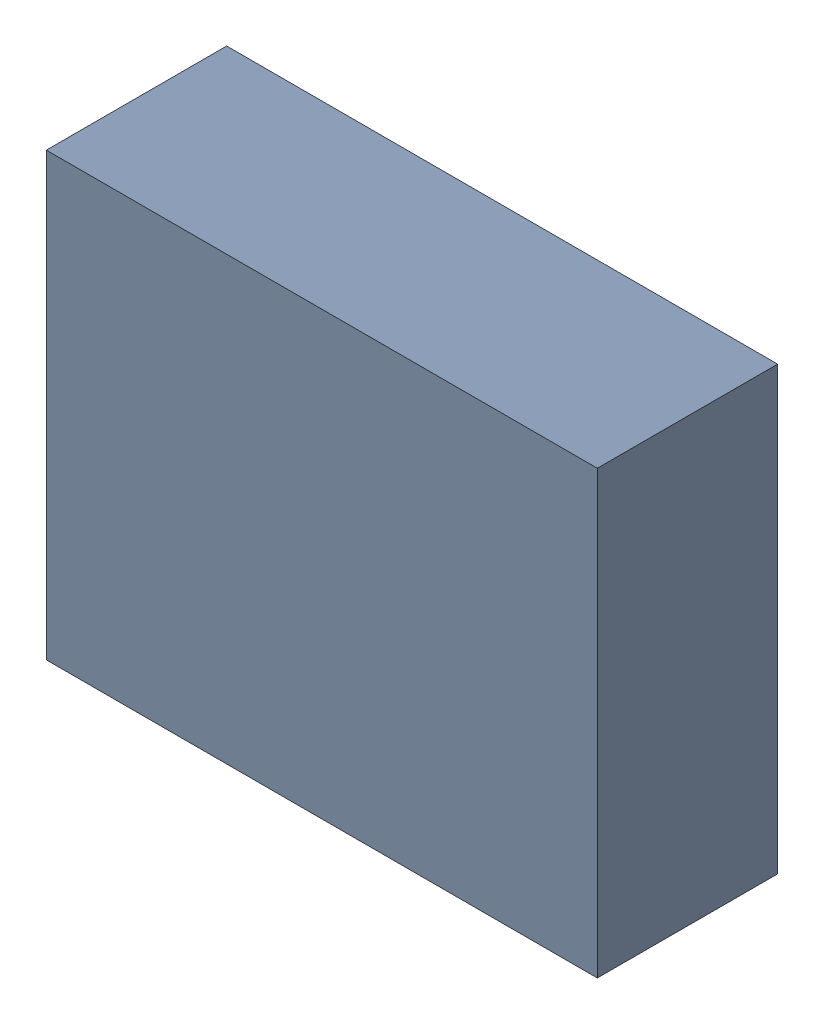
SolidWorks assembly U1, configuration Default. Lengths in mm.
Overall size (4.98 3.99 1.63).
2 component instances, 1 part files, 0 mates.
Components (placement in the parent):
- 506292256-1: 506292256 [Default] at (260.35 124.46 0.1127) size (4.98 3.99 1.63)
  - Extruded_9-1: Extruded_9 [Default] at origin size (4.98 3.99 1.63)
